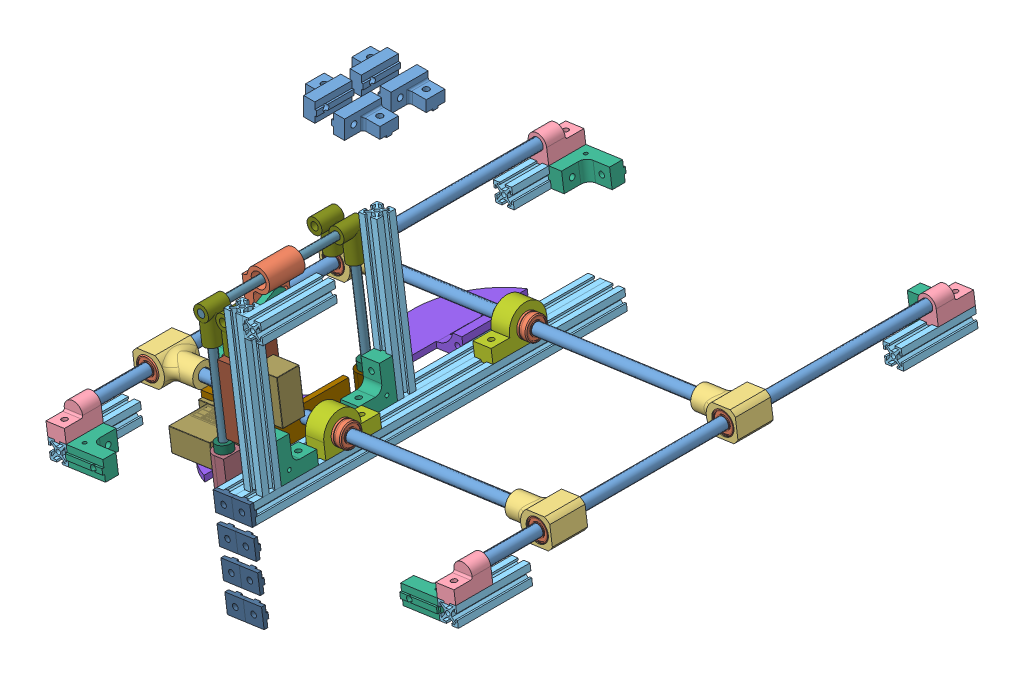
SolidWorks assembly BigRobotFork2019Assembly, configuration Default. Lengths in mm.
Overall size (226.91 110.53 282).
63 component instances, 24 part files, 138 mates.
Components (placement in the parent):
- LinearShaft6mm_differentLengths-1: LinearShaft6mm_differentLengths [250mm] at (75.8296 107.6087 84.7425) size (6 6 250)
- Lineare_bearing_LMUU_serie-1: Lineare_bearing_LMUU_serie [LM6UU] at (75.8296 107.6087 290.7425) x (1 0 0) z (0 -1 0) size (12 19 12)
- LMUU6mm_Support_PerpendicularJunction_Shaft6mm-1: LMUU6mm_Support_PerpendicularJunction_Shaft6mm [Default] at (75.8296 107.6087 290.2425) x (-0.99016 -0.139942 0) z (0 0 1) size (28.5 15.22 19)
- ShaftMakerBeamSupport-1: ShaftMakerBeamSupport [Default] at (75.8296 107.6087 349.7425) x (-0.139942 0.99016 0) z (0 0 -1) size (14 10 20)
- Makerbeam50-1000mm-1: Makerbeam50-1000mm [40mm] at (77.6489 94.7366 349.7425) x (-0.139942 0.99016 0) z (0 0 -1) size (10 10 40)
- Bracket_L_Big_20x20-1: Bracket_L_Big_20x20 [Default] at (81.9 100.3872 349.7425) x (0 0 -1) z (0.139942 -0.99016 0) size (46 46 10)
- Makerbeam50-1000mm-2: Makerbeam50-1000mm [40mm] at (77.6489 94.7366 109.7425) x (-0.139942 0.99016 0) z (0 0 -1) size (10 10 40)
- Bracket_L_Big_20x20-2: Bracket_L_Big_20x20 [Default] at (83.2994 90.4856 69.7425) x (0 0 1) z (-0.139942 0.99016 0) size (46 46 10)
- ShaftMakerBeamSupport-2: ShaftMakerBeamSupport [Default] at (75.8296 107.6087 69.7425) x (-0.139942 0.99016 0) z (0 0 1) size (14 10 20)
- Lineare_bearing_LMUU_serie-2: Lineare_bearing_LMUU_serie [LM6UU] at (75.8296 107.6087 190.2425) x (1 0 0) z (0 -1 0) size (12 19 12)
- LMUU6mm_Support_PerpendicularJunction_Shaft6mm-2: LMUU6mm_Support_PerpendicularJunction_Shaft6mm [Default] at (75.8296 107.6087 190.2425) x (-0.99016 -0.139942 0) z (0 0 1) size (28.5 15.22 19)
- LinearShaft6mm_differentLengths-2: LinearShaft6mm_differentLengths [200mm] at (279.8025 136.4367 190.2425) x (0.121504 -0.859704 -0.49613) z (-0.99016 -0.139942 0) size (6 6 200)
- LinearShaft6mm_differentLengths-3: LinearShaft6mm_differentLengths [200mm] at (279.8025 136.4367 290.2425) x (-0.022059 0.156081 0.987498) z (-0.99016 -0.139942 0) size (6 6 200)
- LMUU6mm_Support_PerpendicularJunction_Shaft6mm-3: LMUU6mm_Support_PerpendicularJunction_Shaft6mm [Default] at (285.7435 137.2764 190.2425) x (0.99016 0.139942 0) z (0 0 1) size (28.5 15.22 19)
- LMUU6mm_Support_PerpendicularJunction_Shaft6mm-4: LMUU6mm_Support_PerpendicularJunction_Shaft6mm [Default] at (285.7435 137.2764 290.2425) x (0.99016 0.139942 0) z (0 0 1) size (28.5 15.22 19)
- LinearShaft6mm_differentLengths-4: LinearShaft6mm_differentLengths [250mm] at (285.7435 137.2764 84.7425) size (6 6 250)
- Lineare_bearing_LMUU_serie-3: Lineare_bearing_LMUU_serie [LM6UU] at (285.7435 137.2764 190.2425) x (1 0 0) z (0 -1 0) size (12 19 12)
- Lineare_bearing_LMUU_serie-4: Lineare_bearing_LMUU_serie [LM6UU] at (285.7435 137.2764 290.2425) x (1 0 0) z (0 -1 0) size (12 19 12)
- ShaftMakerBeamSupport-3: ShaftMakerBeamSupport [Default] at (285.7435 137.2764 349.7425) x (-0.139942 0.99016 0) z (0 0 -1) size (14 10 20)
- Makerbeam50-1000mm-3: Makerbeam50-1000mm [40mm] at (287.5627 124.4043 309.7425) x (-0.139942 0.99016 0) z (0 0 1) size (10 10 40)
- Bracket_L_Big_20x20-3: Bracket_L_Big_20x20 [Default] at (283.3117 118.7538 349.7425) x (0 0 -1) z (-0.139942 0.99016 0) size (46 46 10)
- ShaftMakerBeamSupport-4: ShaftMakerBeamSupport [Default] at (285.7435 137.2764 69.7425) x (-0.139942 0.99016 0) z (0 0 1) size (14 10 20)
- Makerbeam50-1000mm-4: Makerbeam50-1000mm [40mm] at (287.5627 124.4043 69.7425) x (0.99016 0.139942 0) z (0 0 1) size (10 10 40)
- Bracket_L_Big_20x20-4: Bracket_L_Big_20x20 [Default] at (281.9122 128.6554 69.7425) x (0 0 1) z (0.139942 -0.99016 0) size (46 46 10)
- Lineare_bearing_LMUU_serie-5: Lineare_bearing_LMUU_serie [LM6UU] at (166.7867 120.4639 290.2425) x (-0.028348 0.200578 -0.979267) z (0.13704 -0.969631 -0.202572) size (12 19 12)
- Makerbeam50-1000mm-5: Makerbeam50-1000mm [200mm] at (158.2092 106.1224 139.2425) x (0.99016 0.139942 0) z (0 0 1) size (10 10 200)
- Lineare_bearing_LMUU_serie-6: Lineare_bearing_LMUU_serie [LM6UU] at (166.7867 120.4639 190.2425) x (0.127501 -0.902132 -0.412192) z (-0.057683 0.408136 -0.911097) size (12 19 12)
- LM6UU_MakerBeamSupport-2: LM6UU_MakerBeamSupport [Default] at (171.2424 121.0936 190.2425) x (0 0 1) z (-0.99016 -0.139942 0) size (30 19 10)
- ForkBottomBlock-1: ForkBottomBlock [Default] at (147.6079 109.6738 290.2425) x (0 0 -1) z (0.139942 -0.99016 0) size (74.16 41 10)
- ForkBottomBlock-2: ForkBottomBlock [Default] at (147.6079 109.6738 190.2425) x (0 0 -1) z (0.139942 -0.99016 0) size (74.16 41 10)
- ForkRotatingBottomPlateSupport-1: ForkRotatingBottomPlateSupport [Default] at (152.2788 112.3539 290.2425) x (0.139942 -0.99016 0) z (0 0 1) size (24 41 48)
- Makerbeam50-1000mm-6: Makerbeam50-1000mm [200mm] at (168.1108 107.5219 139.2425) x (-0.99016 -0.139942 0) z (0 0 1) size (10 10 200)
- MakerBeamEndSquare3mm-1: MakerBeamEndSquare3mm [Default] at (158.2092 106.1224 339.2425) x (-0.139942 0.99016 0) z (0 0 1) size (55 20 3)
- LM6UU_MakerBeamSupport-3: LM6UU_MakerBeamSupport [Default] at (161.3408 119.6942 290.2425) x (0 0 -1) z (0.99016 0.139942 0) size (30 19 10)
- Makerbeam50-1000mm-7: Makerbeam50-1000mm [80mm] at (156.2158 191.6854 329.2425) x (0.99016 0.139942 0) z (0.139942 -0.99016 0) size (10 10 80)
- Bracket_L_Big_20x20-5: Bracket_L_Big_20x20 [Default] at (162.4603 111.773 324.2425) x (0 0 -1) z (0.99016 0.139942 0) size (46 46 10)
- MG90s_servoSupport1-1: MG90s_servoSupport1 [Default] at (150.2814 147.9243 324.2425) x (0 0 1) z (-0.139942 0.99016 0) size (25 12 35)
- MG90s_servo-1: MG90s_servo [Default] at (150.2464 148.1719 317.7425) x (-0.139942 0.99016 0) z (0.99016 0.139942 0) size (32.5 12 34)
- LM4UU_MakerBeamSupport_DoubleLength-1: LM4UU_MakerBeamSupport_DoubleLength [Default] at (149.0073 99.7722 328.7425) x (0 0 -1) z (-0.139942 0.99016 0) size (20 11.5 20)
- LinearShaft4mm_differentLengths-1: LinearShaft4mm_differentLengths [85mm] at (137.8431 178.7652 328.7425) x (0.989185 0.139804 -0.044354) z (0.139942 -0.99016 0) size (4 4 85)
- Lineare_bearing_LM4UU-1: Lineare_bearing_LM4UU [Default] at (148.1677 105.7132 328.7425) x (0.139942 -0.99016 0) z (-0.471678 -0.066663 0.879247) size (12 8 8)
- Lineare_bearing_LM4UU-2: Lineare_bearing_LM4UU [Default] at (146.4884 117.5951 328.7425) x (-0.139942 0.99016 0) z (0.301825 0.042658 0.952409) size (12 8 8)
- LinearShaft4mm_PerpendicularJuntion-1: LinearShaft4mm_PerpendicularJuntion [Default] at (137.5632 180.7455 332.7425) x (-0.139942 0.99016 0) z (0 0 -1) size (19 20 12)
- MG90s_servo-2: MG90s_servo [Default] at (128.8378 112.0707 308.5425) x (0.99016 0.139942 0) z (0 0 1) size (32.5 12 34)
- MG90s_armSingle-1: MG90s_armSingle [Default] at (134.0361 112.8054 295.5425) x (-0.759643 -0.65034 0) z (0 0 1) size (24 6.8 2)
- LinearShaft4mm_PerpendicularJuntion-2: LinearShaft4mm_PerpendicularJuntion [Default] at (137.5632 180.7455 247.7425) x (-0.139942 0.99016 0) z (0 0 1) size (19 20 12)
- LinearShaft4mm_differentLengths-2: LinearShaft4mm_differentLengths [85mm] at (149.7381 94.6016 251.7425) x (0.912888 0.129021 0.387285) z (-0.139942 0.99016 0) size (4 4 85)
- LM4UU_MakerBeamSupport_DoubleLengthRight-1: LM4UU_MakerBeamSupport_DoubleLengthRight [Default] at (150.4068 89.8706 251.7425) x (0 0 1) z (0.139942 -0.99016 0) size (20 11.5 20)
- Lineare_bearing_LM4UU-3: Lineare_bearing_LM4UU [Default] at (148.1677 105.7132 251.7425) x (0.139942 -0.99016 0) z (0 0 1) size (12 8 8)
- Lineare_bearing_LM4UU-4: Lineare_bearing_LM4UU [Default] at (146.4884 117.5951 251.7425) x (0.139942 -0.99016 0) z (0 0 1) size (12 8 8)
- LinearShaft4mm_differentLengths-3: LinearShaft4mm_differentLengths [85mm] at (137.5632 180.7455 247.7425) size (4 4 85)
- Makerbeam50-1000mm-8: Makerbeam50-1000mm [40mm] at (166.8171 188.1341 294.2425) x (-0.99016 -0.139942 0) z (0 0 1) size (10 10 40)
- Bracket_L20x15_CrossBig-1: Bracket_L20x15_CrossBig [Default] at (98.3213 189.6121 177.1609) size (40 11 45)
- Bracket_L_Big_20x20-6: Bracket_L_Big_20x20 [Default] at (162.4603 111.773 251.7425) x (0 0 1) z (-0.99016 -0.139942 0) size (46 46 10)
- Makerbeam50-1000mm-9: Makerbeam50-1000mm [80mm] at (146.3142 190.286 246.7425) x (0.99016 0.139942 0) z (0.139942 -0.99016 0) size (10 10 80)
- LM4UUSupport_WithRollingBallSupport-1: LM4UUSupport_WithRollingBallSupport [Default] at (137.5632 180.7455 292.2268) x (0.139942 -0.99016 0) z (0 0 1) size (26 15 19)
- Lineare_bearing_LM4UU-5: Lineare_bearing_LM4UU [Default] at (137.5632 180.7455 288.7268) x (0 0 -1) z (0.745964 -0.665986 0) size (12 8 8)
- -MR623ZZ-assem-1: -MR623ZZ-assem [Default] at (133.4415 167.0338 292.2268) x (0.99016 0.139942 0) z (0 0 1) size (4 10 10)
  - mr623zz-cen-1: mr623zz-cen [Default] at (0.5 0 0) size (0.23 8.2 8.2)
  - mr623zz-ext-1: mr623zz-ext [Default] at origin size (4 10 10)
  - mr623zz-int-1: mr623zz-int [Default] at origin size (4 5.2 5.2)
  - mr623zz-cen-2: mr623zz-cen [Default] at (-0.5 0 0) x (-1 0 0) z (0 0 1) size (0.23 8.2 8.2)
- MG90SFlatRudderExtension30mm-1: MG90SFlatRudderExtension30mm [Default] at (138.6199 151.8309 317.7425) x (-0.0736 0.520758 -0.850525) z (0.99016 0.139942 0) size (43 16 4.5)
Mates (geometry in assembly coordinates):
- Concentric1: concentric anti-aligned: cylinder of LinearShaft6mm_differentLengths-1 through (75.8296 107.6087 334.7425) axis (0 0 -1) radius 3; cylinder of Lineare_bearing_LMUU_serie-1 through (75.8296 107.6087 300.2425) axis (0 0 1) radius 3
- Concentric2: concentric anti-aligned: cylinder of Lineare_bearing_LMUU_serie-1 through (75.8296 107.6087 300.2425) axis (0 0 1) radius 6; cylinder of LMUU6mm_Support_PerpendicularJunction_Shaft6mm-1 through (75.8296 107.6087 299.7425) axis (0 0 -1) radius 6
- Coincident1: coincident aligned: plane of Lineare_bearing_LMUU_serie-1 through (75.8296 107.6087 299.7425) normal (0 0 1); circle of LMUU6mm_Support_PerpendicularJunction_Shaft6mm-1
- Concentric3: concentric aligned: cylinder of LinearShaft6mm_differentLengths-1 through (75.8296 107.6087 334.7425) axis (0 0 -1) radius 3; cylinder of ShaftMakerBeamSupport-1 through (75.8296 107.6087 334.7425) axis (0 0 -1) radius 3.1
- Coincident2: coincident anti-aligned: plane of ShaftMakerBeamSupport-1 through (81.9 100.3872 329.7425) normal (0.139942 -0.99016 0); plane of Makerbeam50-1000mm-1 through (81.9 100.3872 309.7425) normal (-0.139942 0.99016 0)
- Coincident3: coincident aligned: plane of ShaftMakerBeamSupport-1 through (81.9 100.3872 329.7425) normal (0.99016 0.139942 0); plane of Makerbeam50-1000mm-1 through (82.3898 96.9216 309.7425) normal (0.99016 0.139942 0)
- Coincident4: coincident anti-aligned: plane of LinearShaft6mm_differentLengths-1 through (75.8296 107.6087 334.7425) normal (0 0 1); plane of ShaftMakerBeamSupport-1 through (75.8296 107.6087 334.7425) normal (0 0 -1)
- Coincident5: coincident anti-aligned: plane of Makerbeam50-1000mm-1 through (82.3898 96.9216 309.7425) normal (0.99016 0.139942 0); plane of Bracket_L_Big_20x20-1 through (83.2994 90.4856 349.7425) normal (-0.99016 -0.139942 0)
- Coincident6: coincident aligned: plane of Makerbeam50-1000mm-1 through (79.8338 89.9958 309.7425) normal (0.139942 -0.99016 0); plane of Bracket_L_Big_20x20-1 through (94.1911 92.0249 338.7425) normal (0.139942 -0.99016 0)
- Coincident7: coincident aligned: plane of Makerbeam50-1000mm-1 through (77.6489 94.7366 349.7425) normal (0 0 1); plane of Bracket_L_Big_20x20-1 through (103.1026 93.2844 349.7425) normal (0 0 1)
- Concentric4: concentric anti-aligned: cylinder of LinearShaft6mm_differentLengths-1 through (75.8296 107.6087 334.7425) axis (0 0 -1) radius 3; cylinder of ShaftMakerBeamSupport-2 through (75.8296 107.6087 84.7425) axis (0 0 1) radius 3.1
- Coincident8: coincident anti-aligned: plane of LinearShaft6mm_differentLengths-1 through (75.8296 107.6087 84.7425) normal (0 0 -1); plane of ShaftMakerBeamSupport-2 through (75.8296 107.6087 84.7425) normal (0 0 1)
- Coincident9: coincident aligned: plane of ShaftMakerBeamSupport-1 through (81.9 100.3872 329.7425) normal (0.139942 -0.99016 0); plane of ShaftMakerBeamSupport-2 through (71.9984 98.9877 89.7425) normal (0.139942 -0.99016 0)
- Coincident10: coincident aligned: plane of ShaftMakerBeamSupport-1 through (75.8296 107.6087 349.7425) normal (0 0 1); plane of Makerbeam50-1000mm-1 through (77.6489 94.7366 349.7425) normal (0 0 1)
- Parallel1: parallel aligned: plane of LMUU6mm_Support_PerpendicularJunction_Shaft6mm-1 through (81.8052 100.8787 280.7425) normal (0.139942 -0.99016 0); plane of Makerbeam50-1000mm-2 through (79.8338 89.9958 69.7425) normal (0.139942 -0.99016 0)
- Concentric5: concentric anti-aligned: cylinder of LinearShaft6mm_differentLengths-1 through (75.8296 107.6087 334.7425) axis (0 0 -1) radius 3; cylinder of Lineare_bearing_LMUU_serie-2 through (75.8296 107.6087 199.7425) axis (0 0 1) radius 3
- Concentric6: concentric anti-aligned: cylinder of Lineare_bearing_LMUU_serie-2 through (75.8296 107.6087 199.7425) axis (0 0 1) radius 6; cylinder of LMUU6mm_Support_PerpendicularJunction_Shaft6mm-2 through (75.8296 107.6087 199.7425) axis (0 0 -1) radius 6
- Coincident12: coincident aligned: plane of Lineare_bearing_LMUU_serie-2 through (78.8296 107.6087 199.7425) normal (0 0 1); plane of LMUU6mm_Support_PerpendicularJunction_Shaft6mm-2 through (75.8296 107.6087 199.7425) normal (0 0 1)
- Coincident13: coincident aligned: plane of LMUU6mm_Support_PerpendicularJunction_Shaft6mm-1 through (79.7061 115.7311 280.7425) normal (-0.139942 0.99016 0); plane of LMUU6mm_Support_PerpendicularJunction_Shaft6mm-2 through (79.7061 115.7311 180.7425) normal (-0.139942 0.99016 0)
- Concentric7: concentric anti-aligned: cylinder of LMUU6mm_Support_PerpendicularJunction_Shaft6mm-2 through (96.623 110.5475 190.2425) axis (-0.99016 -0.139942 0) radius 3; cylinder of LinearShaft6mm_differentLengths-2 through (81.7706 108.4484 190.2425) axis (0.99016 0.139942 0) radius 3
- Tangent1: tangent anti-aligned: cylinder of Lineare_bearing_LMUU_serie-2 through (75.8296 107.6087 199.7425) axis (0 0 1) radius 6; plane of LinearShaft6mm_differentLengths-2 through (81.7706 108.4484 190.2425) normal (-0.99016 -0.139942 0)
- Concentric8: concentric anti-aligned: cylinder of LMUU6mm_Support_PerpendicularJunction_Shaft6mm-1 through (96.623 110.5475 290.2425) axis (-0.99016 -0.139942 0) radius 3; cylinder of LinearShaft6mm_differentLengths-3 through (81.7706 108.4484 290.2425) axis (0.99016 0.139942 0) radius 3
- Tangent2: tangent anti-aligned: cylinder of Lineare_bearing_LMUU_serie-1 through (75.8296 107.6087 300.2425) axis (0 0 1) radius 6; plane of LinearShaft6mm_differentLengths-3 through (81.7706 108.4484 290.2425) normal (-0.99016 -0.139942 0)
- Concentric9: concentric aligned: cylinder of LinearShaft6mm_differentLengths-2 through (81.7706 108.4484 190.2425) axis (0.99016 0.139942 0) radius 3; cylinder of LMUU6mm_Support_PerpendicularJunction_Shaft6mm-3 through (264.9502 134.3376 190.2425) axis (0.99016 0.139942 0) radius 3
- Tangent3: tangent anti-aligned: plane of LinearShaft6mm_differentLengths-2 through (279.8025 136.4367 190.2425) normal (0.99016 0.139942 0); cylinder of LMUU6mm_Support_PerpendicularJunction_Shaft6mm-3 through (285.7435 137.2764 199.7425) axis (0 0 -1) radius 6
- Coincident14: coincident aligned: plane of LMUU6mm_Support_PerpendicularJunction_Shaft6mm-2 through (81.8052 100.8787 180.7425) normal (0.139942 -0.99016 0); plane of LMUU6mm_Support_PerpendicularJunction_Shaft6mm-3 through (281.8671 129.154 180.7425) normal (0.139942 -0.99016 0)
- Concentric10: concentric aligned: cylinder of LinearShaft6mm_differentLengths-3 through (81.7706 108.4484 290.2425) axis (0.99016 0.139942 0) radius 3; cylinder of LMUU6mm_Support_PerpendicularJunction_Shaft6mm-4 through (264.9502 134.3376 290.2425) axis (0.99016 0.139942 0) radius 3
- Tangent4: tangent anti-aligned: plane of LinearShaft6mm_differentLengths-3 through (279.8025 136.4367 290.2425) normal (0.99016 0.139942 0); cylinder of LMUU6mm_Support_PerpendicularJunction_Shaft6mm-4 through (285.7435 137.2764 299.7425) axis (0 0 -1) radius 6
- Concentric11: concentric anti-aligned: cylinder of LMUU6mm_Support_PerpendicularJunction_Shaft6mm-3 through (285.7435 137.2764 199.7425) axis (0 0 -1) radius 6; cylinder of Lineare_bearing_LMUU_serie-3 through (285.7435 137.2764 199.7425) axis (0 0 1) radius 6
- Coincident15: coincident aligned: plane of LMUU6mm_Support_PerpendicularJunction_Shaft6mm-3 through (285.7435 137.2764 180.7425) normal (0 0 -1); plane of Lineare_bearing_LMUU_serie-3 through (291.2435 137.2764 180.7425) normal (0 0 -1)
- Concentric12: concentric anti-aligned: cylinder of LMUU6mm_Support_PerpendicularJunction_Shaft6mm-4 through (285.7435 137.2764 299.7425) axis (0 0 -1) radius 6; cylinder of Lineare_bearing_LMUU_serie-4 through (285.7435 137.2764 299.7425) axis (0 0 1) radius 6
- Coincident16: coincident aligned: plane of LMUU6mm_Support_PerpendicularJunction_Shaft6mm-4 through (285.7435 137.2764 280.7425) normal (0 0 -1); plane of Lineare_bearing_LMUU_serie-4 through (291.2435 137.2764 280.7425) normal (0 0 -1)
- Concentric13: concentric anti-aligned: cylinder of LinearShaft6mm_differentLengths-4 through (285.7435 137.2764 334.7425) axis (0 0 -1) radius 3; cylinder of Lineare_bearing_LMUU_serie-3 through (285.7435 137.2764 199.7425) axis (0 0 1) radius 3
- Concentric14: concentric aligned: cylinder of LinearShaft6mm_differentLengths-4 through (285.7435 137.2764 334.7425) axis (0 0 -1) radius 3; cylinder of ShaftMakerBeamSupport-3 through (285.7435 137.2764 334.7425) axis (0 0 -1) radius 3.1
- Coincident17: coincident anti-aligned: plane of LinearShaft6mm_differentLengths-4 through (285.7435 137.2764 334.7425) normal (0 0 1); plane of ShaftMakerBeamSupport-3 through (285.7435 137.2764 334.7425) normal (0 0 -1)
- Coincident18: coincident anti-aligned: plane of ShaftMakerBeamSupport-3 through (291.8138 130.0548 329.7425) normal (0.139942 -0.99016 0); plane of Makerbeam50-1000mm-3 through (281.9122 128.6554 349.7425) normal (-0.139942 0.99016 0)
- Coincident19: coincident aligned: plane of ShaftMakerBeamSupport-3 through (291.8138 130.0548 329.7425) normal (0.99016 0.139942 0); plane of Makerbeam50-1000mm-3 through (292.3036 126.5892 349.7425) normal (0.99016 0.139942 0)
- Parallel3: parallel aligned: plane of Makerbeam50-1000mm-1 through (73.3978 89.0861 309.7425) normal (0.139942 -0.99016 0); plane of Makerbeam50-1000mm-3 through (293.2133 120.1532 349.7425) normal (0.139942 -0.99016 0)
- Coincident22: coincident aligned: plane of Makerbeam50-1000mm-1 through (77.6489 94.7366 349.7425) normal (0 0 1); plane of Makerbeam50-1000mm-3 through (287.5627 124.4043 349.7425) normal (0 0 1)
- Coincident23: coincident aligned: plane of ShaftMakerBeamSupport-3 through (285.7435 137.2764 349.7425) normal (0 0 1); plane of Makerbeam50-1000mm-3 through (287.5627 124.4043 349.7425) normal (0 0 1)
- Coincident24: coincident anti-aligned: plane of Makerbeam50-1000mm-3 through (283.3117 118.7538 349.7425) normal (-0.99016 -0.139942 0); plane of Bracket_L_Big_20x20-3 through (281.9122 128.6554 349.7425) normal (0.99016 0.139942 0)
- Coincident25: coincident aligned: plane of Makerbeam50-1000mm-3 through (287.5627 124.4043 349.7425) normal (0 0 1); plane of Bracket_L_Big_20x20-3 through (262.109 125.8566 349.7425) normal (0 0 1)
- Coincident26: coincident aligned: plane of Makerbeam50-1000mm-3 through (286.7772 119.2436 349.7425) normal (0.139942 -0.99016 0); plane of Bracket_L_Big_20x20-3 through (272.4199 117.2144 338.7425) normal (0.139942 -0.99016 0)
- Concentric15: concentric anti-aligned: cylinder of LinearShaft6mm_differentLengths-4 through (285.7435 137.2764 334.7425) axis (0 0 -1) radius 3; cylinder of ShaftMakerBeamSupport-4 through (285.7435 137.2764 84.7425) axis (0 0 1) radius 3.1
- Coincident27: coincident anti-aligned: plane of LinearShaft6mm_differentLengths-4 through (285.7435 137.2764 84.7425) normal (0 0 -1); plane of ShaftMakerBeamSupport-4 through (285.7435 137.2764 84.7425) normal (0 0 1)
- Coincident28: coincident aligned: plane of ShaftMakerBeamSupport-3 through (285.8834 136.2862 349.7425) normal (-0.139942 0.99016 0); plane of ShaftMakerBeamSupport-4 through (285.8834 136.2862 69.7425) normal (-0.139942 0.99016 0)
- Coincident29: coincident anti-aligned: plane of ShaftMakerBeamSupport-4 through (288.2988 129.558 89.7425) normal (0.139942 -0.99016 0); plane of Makerbeam50-1000mm-4 through (288.3483 129.565 109.7425) normal (-0.139942 0.99016 0)
- Coincident30: coincident aligned: plane of ShaftMakerBeamSupport-4 through (291.8138 130.0548 89.7425) normal (0.99016 0.139942 0); plane of Makerbeam50-1000mm-4 through (291.8138 130.0548 109.7425) normal (0.99016 0.139942 0)
- Coincident31: coincident aligned: plane of Makerbeam50-1000mm-2 through (77.6489 94.7366 69.7425) normal (0 0 -1); plane of Makerbeam50-1000mm-4 through (287.5627 124.4043 69.7425) normal (0 0 -1)
- Coincident32: coincident aligned: plane of Makerbeam50-1000mm-4 through (286.7772 119.2436 109.7425) normal (0.139942 -0.99016 0); plane of Bracket_L_Big_20x20-4 through (272.4199 117.2144 80.7425) normal (0.139942 -0.99016 0)
- Coincident33: coincident anti-aligned: plane of Makerbeam50-1000mm-4 through (283.3117 118.7538 109.7425) normal (-0.99016 -0.139942 0); plane of Bracket_L_Big_20x20-4 through (283.3117 118.7538 69.7425) normal (0.99016 0.139942 0)
- Coincident34: coincident aligned: plane of Makerbeam50-1000mm-4 through (287.5627 124.4043 69.7425) normal (0 0 -1); plane of Bracket_L_Big_20x20-4 through (263.5085 115.955 69.7425) normal (0 0 -1)
- Distance1: distance = 4.5 mm aligned: plane of Lineare_bearing_LMUU_serie-5; plane of ? through (245.1356 52.8542 137.3823) normal (0.936759 -0.349976 0)
- Concentric17: concentric aligned: cylinder of LinearShaft6mm_differentLengths-3 through (81.7706 108.4484 290.2425) axis (0.99016 0.139942 0) radius 3; cylinder of Lineare_bearing_LMUU_serie-5 through (176.1932 121.7934 290.2425) axis (0.99016 0.139942 0) radius 3
- Coincident36: coincident anti-aligned: plane of ? through (242.3358 45.3602 147.3823) normal (-0.349976 -0.936759 0); plane of Makerbeam50-1000mm-5
- Concentric18: concentric anti-aligned: cylinder of LinearShaft6mm_differentLengths-2 through (81.7706 108.4484 190.2425) axis (0.99016 0.139942 0) radius 3; cylinder of Lineare_bearing_LMUU_serie-6 through (157.3801 119.1345 190.2425) axis (-0.99016 -0.139942 0) radius 3
- Coincident38: coincident anti-aligned: plane of Makerbeam50-1000mm-5 through (158.9948 111.2832 339.2425) normal (-0.139942 0.99016 0); plane of LM6UU_MakerBeamSupport-2 through (162.4603 111.773 180.2425) normal (0.139942 -0.99016 0)
- Coincident40: coincident aligned: plane of Lineare_bearing_LMUU_serie-5 through (175.6981 121.7234 290.2425) normal (0.99016 0.139942 0); plane of Lineare_bearing_LMUU_serie-6 through (175.6981 121.7234 190.2425) normal (0.99016 0.139942 0)
- Concentric20: concentric aligned: cylinder of ForkBottomBlock-1 through (145.3371 104.3032 253.1615) axis (0 0 1) radius 1.5; cylinder of ForkRotatingBottomPlateSupport-1 through (145.3371 104.3032 266.2425) axis (0 0 1) radius 1.25
- Coincident41: coincident anti-aligned: plane of ForkBottomBlock-1 through (134.1549 97.6731 302.2425) normal (0 0 1); plane of ForkRotatingBottomPlateSupport-1 through (114.3517 94.8743 302.2425) normal (0 0 -1)
- Coincident42: coincident anti-aligned: plane of Makerbeam50-1000mm-5 through (153.9581 100.4719 339.2425) normal (-0.99016 -0.139942 0); plane of ForkRotatingBottomPlateSupport-1 through (153.4613 103.987 314.2425) normal (0.99016 0.139942 0)
- Coincident44: coincident aligned: plane of Makerbeam50-1000mm-5 through (158.2092 106.1224 339.2425) normal (0 0 1); plane of Makerbeam50-1000mm-6 through (168.1108 107.5219 339.2425) normal (0 0 1)
- Coincident45: coincident anti-aligned: plane of Makerbeam50-1000mm-5 through (163.3699 105.3369 339.2425) normal (0.99016 0.139942 0); plane of Makerbeam50-1000mm-6 through (163.8597 101.8714 339.2425) normal (-0.99016 -0.139942 0)
- Coincident46: coincident aligned: plane of Makerbeam50-1000mm-5 through (157.4237 100.9617 339.2425) normal (0.139942 -0.99016 0); plane of Makerbeam50-1000mm-6 through (167.3253 102.3611 339.2425) normal (0.139942 -0.99016 0)
- Concentric21: concentric aligned: cylinder of Makerbeam50-1000mm-6 through (168.1108 107.5219 339.2425) axis (0 0 -1) radius 1.25; cylinder of MakerBeamEndSquare3mm-1 through (168.1108 107.5219 341.2425) axis (0 0 -1) radius 1.5
- Coincident47: coincident anti-aligned: plane of Makerbeam50-1000mm-6 through (168.1108 107.5219 339.2425) normal (0 0 1); plane of MakerBeamEndSquare3mm-1 through (168.1108 107.5219 339.2425) normal (0 0 -1)
- Concentric22: concentric aligned: cylinder of Makerbeam50-1000mm-5 through (158.2092 106.1224 339.2425) axis (0 0 -1) radius 1.25; cylinder of MakerBeamEndSquare3mm-1 through (158.2092 106.1224 341.2425) axis (0 0 -1) radius 1.5
- Coincident48: coincident aligned: plane of LM6UU_MakerBeamSupport-2 through (171.2424 121.0936 190.2425) normal (0.99016 0.139942 0); plane of Makerbeam50-1000mm-6 through (172.3619 113.1724 339.2425) normal (0.99016 0.139942 0)
- Distance3: distance = 5 mm aligned: plane of Lineare_bearing_LMUU_serie-6 through (176.8944 116.8316 187.9755) normal (0.99016 0.139942 0); plane of LM6UU_MakerBeamSupport-2 through (171.2424 121.0936 190.2425) normal (0.99016 0.139942 0)
- Concentric25: concentric anti-aligned: cylinder of Lineare_bearing_LMUU_serie-6 through (157.3801 119.1345 190.2425) axis (-0.99016 -0.139942 0) radius 6; cylinder of LM6UU_MakerBeamSupport-2 through (161.3408 119.6942 190.2425) axis (0.99016 0.139942 0) radius 6
- Concentric27: concentric anti-aligned: cylinder of Lineare_bearing_LMUU_serie-5 through (176.1932 121.7934 290.2425) axis (0.99016 0.139942 0) radius 6; cylinder of LM6UU_MakerBeamSupport-3 through (171.2424 121.0936 290.2425) axis (-0.99016 -0.139942 0) radius 6
- Coincident50: coincident aligned: plane of LM6UU_MakerBeamSupport-2 through (171.2424 121.0936 190.2425) normal (0.99016 0.139942 0); plane of LM6UU_MakerBeamSupport-3 through (171.2424 121.0936 290.2425) normal (0.99016 0.139942 0)
- Coincident51: coincident aligned: plane of LM6UU_MakerBeamSupport-2 through (161.4807 118.7041 210.2425) normal (-0.139942 0.99016 0); plane of LM6UU_MakerBeamSupport-3 through (171.3823 120.1035 270.2425) normal (-0.139942 0.99016 0)
- Distance4: distance = 60 mm anti-aligned: plane of LM6UU_MakerBeamSupport-2 through (162.4603 111.773 210.2425) normal (0 0 1); plane of LM6UU_MakerBeamSupport-3 through (172.3619 113.1724 270.2425) normal (0 0 -1)
- Coincident53: coincident anti-aligned: plane of Makerbeam50-1000mm-6 through (168.8964 112.6826 339.2425) normal (-0.139942 0.99016 0); plane of Makerbeam50-1000mm-7 through (167.4111 112.4727 329.2425) normal (0.139942 -0.99016 0)
- Coincident54: coincident aligned: plane of Makerbeam50-1000mm-6 through (172.3619 113.1724 339.2425) normal (0.99016 0.139942 0); plane of Makerbeam50-1000mm-7 through (172.3619 113.1724 327.7425) normal (0.99016 0.139942 0)
- Distance5: distance = 5 mm: line of MakerBeamEndSquare3mm-1 through (165.9754 112.2697 339.2425) axis (-0.99016 -0.139942 0); plane of Makerbeam50-1000mm-7 through (162.4603 111.773 334.2425) normal (0 0 1)
- Coincident56: coincident aligned: plane of Makerbeam50-1000mm-6 through (172.3619 113.1724 339.2425) normal (0.99016 0.139942 0); plane of Bracket_L_Big_20x20-5 through (170.8226 124.0641 313.2425) normal (0.99016 0.139942 0)
- Coincident57: coincident anti-aligned: plane of Makerbeam50-1000mm-7 through (168.8964 112.6826 324.2425) normal (0 0 -1); plane of Bracket_L_Big_20x20-5 through (169.5631 132.9756 324.2425) normal (0 0 1)
- Coincident58: coincident anti-aligned: plane of Makerbeam50-1000mm-6 through (168.8964 112.6826 339.2425) normal (-0.139942 0.99016 0); plane of Bracket_L_Big_20x20-5 through (172.3619 113.1724 324.2425) normal (0.139942 -0.99016 0)
- Distance6: distance = 4 mm anti-aligned: plane of LM6UU_MakerBeamSupport-3 through (171.2424 121.0936 300.2425) normal (0 0 1); plane of Bracket_L_Big_20x20-5 through (172.3619 113.1724 304.2425) normal (0 0 -1)
- Coincident61: coincident aligned: plane of Makerbeam50-1000mm-7 through (168.8964 112.6826 334.2425) normal (0 0 1); plane of MG90s_servoSupport1-1 through (147.8324 165.2521 334.2425) normal (0 0 1)
- Distance7: distance = 30 mm aligned: plane of MG90s_servoSupport1-1 through (152.7304 130.5966 324.2425) normal (0.139942 -0.99016 0); plane of Makerbeam50-1000mm-6 through (173.7613 103.2708 339.2425) normal (0.139942 -0.99016 0)
- Coincident63: coincident anti-aligned: plane of MG90s_servoSupport1-1 through (147.8324 165.2521 309.2425) normal (-0.99016 -0.139942 0); plane of MG90s_servo-1 through (150.2464 148.1719 317.7425) normal (0.99016 0.139942 0)
- Coincident64: coincident anti-aligned: plane of MG90s_servoSupport1-1 through (146.9399 135.8378 311.7425) normal (0 0 1); plane of MG90s_servo-1 through (147.969 147.85 311.7425) normal (0 0 -1)
- Coincident65: coincident anti-aligned: plane of MG90s_servoSupport1-1 through (143.7213 158.6115 311.7425) normal (0.139942 -0.99016 0); plane of MG90s_servo-1 through (169.4654 162.25 311.7425) normal (-0.139942 0.99016 0)
- Coincident66: coincident aligned: plane of Makerbeam50-1000mm-5 through (157.4237 100.9617 339.2425) normal (0.139942 -0.99016 0); plane of LM4UU_MakerBeamSupport_DoubleLength-1 through (149.0073 99.7722 328.7425) normal (0.139942 -0.99016 0)
- Coincident67: coincident anti-aligned: plane of Makerbeam50-1000mm-5 through (153.9581 100.4719 339.2425) normal (-0.99016 -0.139942 0); plane of LM4UU_MakerBeamSupport_DoubleLength-1 through (152.5587 110.3735 334.2425) normal (0.99016 0.139942 0)
- Coincident68: coincident anti-aligned: plane of ForkRotatingBottomPlateSupport-1 through (152.2788 112.3539 314.2425) normal (0 0 1); plane of LM4UU_MakerBeamSupport_DoubleLength-1 through (152.5587 110.3735 314.2425) normal (0 0 -1)
- Distance8: distance = 5 mm: plane of LM4UU_MakerBeamSupport_DoubleLength-1 through (147.6079 109.6738 334.2425) normal (0 0 1); line of MakerBeamEndSquare3mm-1 through (153.4613 103.987 339.2425) axis (0.139942 -0.99016 0)
- Concentric28: concentric anti-aligned: cylinder of LM4UU_MakerBeamSupport_DoubleLength-1 through (147.6079 109.6738 328.7425) axis (0.139942 -0.99016 0) radius 4; cylinder of LinearShaft4mm_differentLengths-1 through (149.7381 94.6016 328.7425) axis (-0.139942 0.99016 0) radius 2
- Concentric29: concentric anti-aligned: cylinder of LM4UU_MakerBeamSupport_DoubleLength-1 through (147.6079 109.6738 328.7425) axis (0.139942 -0.99016 0) radius 4; cylinder of Lineare_bearing_LM4UU-1 through (149.0073 99.7722 328.7425) axis (-0.139942 0.99016 0) radius 4
- Coincident70: coincident aligned: plane of LM4UU_MakerBeamSupport_DoubleLength-1 through (149.0073 99.7722 328.7425) normal (0.139942 -0.99016 0); plane of Lineare_bearing_LM4UU-1 through (152.4897 100.2644 330.648) normal (0.139942 -0.99016 0)
- Concentric30: concentric anti-aligned: cylinder of LinearShaft4mm_differentLengths-1 through (149.7381 94.6016 328.7425) axis (-0.139942 0.99016 0) radius 2; cylinder of Lineare_bearing_LM4UU-2 through (145.6487 123.5361 328.7425) axis (0.139942 -0.99016 0) radius 2
- Coincident71: coincident anti-aligned: plane of Lineare_bearing_LM4UU-1 through (149.0692 111.9002 329.6953) normal (-0.139942 0.99016 0); plane of Lineare_bearing_LM4UU-2 through (145.442 111.3876 329.3522) normal (0.139942 -0.99016 0)
- Concentric32: concentric aligned: cylinder of LinearShaft4mm_differentLengths-1 through (149.7381 94.6016 328.7425) axis (-0.139942 0.99016 0) radius 2; cylinder of LinearShaft4mm_PerpendicularJuntion-1 through (139.6623 165.8931 328.7425) axis (-0.139942 0.99016 0) radius 2
- Tangent6: tangent anti-aligned: plane of LinearShaft4mm_differentLengths-1 through (137.8431 178.7652 328.7425) normal (-0.139942 0.99016 0); cylinder of LinearShaft4mm_PerpendicularJuntion-1 through (137.5632 180.7455 320.7425) axis (0 0 1) radius 2
- Concentric33: concentric anti-aligned: cylinder of MG90s_servo-2 through (134.0361 112.8054 295.5425) axis (0 0 1) radius 2.275; cylinder of MG90s_armSingle-1 through (134.0361 112.8054 297.5425) axis (0 0 -1) radius 1.25
- Coincident73: coincident aligned: plane of MG90s_servo-2 through (134.0361 112.8054 295.5425) normal (0 0 -1); plane of MG90s_armSingle-1 through (134.0361 112.8054 295.5425) normal (0 0 -1)
- Tangent7: tangent anti-aligned: plane of ForkBottomBlock-1 through (143.6367 102.043 327.3235) normal (-0.139942 0.99016 0); cylinder of MG90s_armSingle-1 through (119.9068 100.7091 297.5425) axis (0 0 -1) radius 2
- Coincident82: coincident aligned: plane of Makerbeam50-1000mm-5 through (157.4237 100.9617 339.2425) normal (0.139942 -0.99016 0); plane of ForkBottomBlock-1 through (149.0073 99.7722 290.2425) normal (0.139942 -0.99016 0)
- Concentric34: concentric anti-aligned: cylinder of LinearShaft4mm_PerpendicularJuntion-1 through (137.5632 180.7455 320.7425) axis (0 0 1) radius 2; cylinder of LinearShaft4mm_PerpendicularJuntion-2 through (137.5632 180.7455 259.7425) axis (0 0 -1) radius 2
- Coincident84: coincident anti-aligned: plane of Makerbeam50-1000mm-5 through (153.9581 100.4719 339.2425) normal (-0.99016 -0.139942 0); plane of LM4UU_MakerBeamSupport_DoubleLengthRight-1 through (152.5587 110.3735 246.2425) normal (0.99016 0.139942 0)
- Coincident85: coincident aligned: plane of Makerbeam50-1000mm-5 through (157.4237 100.9617 339.2425) normal (0.139942 -0.99016 0); plane of LM4UU_MakerBeamSupport_DoubleLengthRight-1 through (149.0073 99.7722 251.7425) normal (0.139942 -0.99016 0)
- Coincident86: coincident anti-aligned: plane of ForkRotatingBottomPlateSupport-1 through (152.2788 112.3539 266.2425) normal (0 0 -1); plane of LM4UU_MakerBeamSupport_DoubleLengthRight-1 through (152.5587 110.3735 266.2425) normal (0 0 1)
- Concentric35: concentric anti-aligned: cylinder of LM4UU_MakerBeamSupport_DoubleLengthRight-1 through (147.6079 109.6738 251.7425) axis (0.139942 -0.99016 0) radius 4; cylinder of Lineare_bearing_LM4UU-3 through (149.0073 99.7722 251.7425) axis (-0.139942 0.99016 0) radius 4
- Coincident87: coincident aligned: plane of LM4UU_MakerBeamSupport_DoubleLengthRight-1 through (149.0073 99.7722 251.7425) normal (0.139942 -0.99016 0); plane of Lineare_bearing_LM4UU-3 through (152.968 100.332 251.7425) normal (0.139942 -0.99016 0)
- Coincident88: coincident anti-aligned: plane of Lineare_bearing_LM4UU-3 through (149.3084 111.934 251.7425) normal (-0.139942 0.99016 0); plane of Lineare_bearing_LM4UU-4 through (151.2887 112.2139 251.7425) normal (0.139942 -0.99016 0)
- Concentric36: concentric anti-aligned: cylinder of LM4UU_MakerBeamSupport_DoubleLengthRight-1 through (147.6079 109.6738 251.7425) axis (0.139942 -0.99016 0) radius 4; cylinder of Lineare_bearing_LM4UU-4 through (147.328 111.6541 251.7425) axis (-0.139942 0.99016 0) radius 4
- Concentric37: concentric anti-aligned: cylinder of LinearShaft4mm_differentLengths-2 through (137.8431 178.7652 251.7425) axis (0.139942 -0.99016 0) radius 2; cylinder of Lineare_bearing_LM4UU-4 through (147.328 111.6541 251.7425) axis (-0.139942 0.99016 0) radius 2
- Coincident89: coincident aligned: plane of LinearShaft4mm_differentLengths-1 through (149.7381 94.6016 328.7425) normal (0.139942 -0.99016 0); plane of LinearShaft4mm_differentLengths-2 through (149.7381 94.6016 251.7425) normal (0.139942 -0.99016 0)
- Concentric38: concentric anti-aligned: cylinder of LinearShaft4mm_PerpendicularJuntion-2 through (139.6623 165.8931 251.7425) axis (-0.139942 0.99016 0) radius 2; cylinder of LinearShaft4mm_differentLengths-2 through (137.8431 178.7652 251.7425) axis (0.139942 -0.99016 0) radius 2
- Concentric39: concentric anti-aligned: cylinder of LinearShaft4mm_PerpendicularJuntion-1 through (137.5632 180.7455 320.7425) axis (0 0 1) radius 2; cylinder of LinearShaft4mm_differentLengths-3 through (137.5632 180.7455 332.7425) axis (0 0 -1) radius 2
- Coincident90: coincident aligned: plane of LinearShaft4mm_PerpendicularJuntion-2 through (137.5632 180.7455 247.7425) normal (0 0 -1); plane of LinearShaft4mm_differentLengths-3 through (137.5632 180.7455 247.7425) normal (0 0 -1)
- Coincident91: coincident aligned: plane of Makerbeam50-1000mm-7 through (168.8964 112.6826 334.2425) normal (0 0 1); plane of Makerbeam50-1000mm-8 through (166.8171 188.1341 334.2425) normal (0 0 1)
- Coincident92: coincident anti-aligned: plane of Makerbeam50-1000mm-7 through (172.3619 113.1724 334.2425) normal (0.99016 0.139942 0); plane of Makerbeam50-1000mm-8 through (161.6564 188.9196 334.2425) normal (-0.99016 -0.139942 0)
- Coincident93: coincident aligned: plane of Makerbeam50-1000mm-7 through (156.2158 191.6854 329.2425) normal (-0.139942 0.99016 0); plane of Makerbeam50-1000mm-8 through (167.6026 193.2948 334.2425) normal (-0.139942 0.99016 0)
- Coincident94: coincident anti-aligned: plane of Makerbeam50-1000mm-5 through (158.9948 111.2832 339.2425) normal (-0.139942 0.99016 0); plane of Bracket_L_Big_20x20-6 through (152.5587 110.3735 251.7425) normal (0.139942 -0.99016 0)
- Coincident95: coincident aligned: plane of Makerbeam50-1000mm-5 through (153.0485 106.908 339.2425) normal (-0.99016 -0.139942 0); plane of Bracket_L_Big_20x20-6 through (151.0194 121.2653 262.7425) normal (-0.99016 -0.139942 0)
- Coincident96: coincident anti-aligned: plane of Bracket_L_Big_20x20-6 through (149.7599 130.1767 251.7425) normal (0 0 -1); plane of Makerbeam50-1000mm-9 through (158.9948 111.2832 251.7425) normal (0 0 1)
- Coincident97: coincident anti-aligned: plane of Makerbeam50-1000mm-5 through (158.9948 111.2832 339.2425) normal (-0.139942 0.99016 0); plane of Makerbeam50-1000mm-9 through (157.5095 111.0732 246.7425) normal (0.139942 -0.99016 0)
- Coincident98: coincident aligned: plane of Bracket_L_Big_20x20-6 through (160.921 122.6647 262.7425) normal (0.99016 0.139942 0); plane of Makerbeam50-1000mm-9 through (162.4603 111.773 251.7425) normal (0.99016 0.139942 0)
- Distance13: distance = 72.5 mm anti-aligned: plane of Makerbeam50-1000mm-7 through (168.8964 112.6826 324.2425) normal (0 0 -1); plane of Makerbeam50-1000mm-9 through (158.9948 111.2832 251.7425) normal (0 0 1)
- Concentric40: concentric anti-aligned: cylinder of LinearShaft4mm_differentLengths-3 through (137.5632 180.7455 332.7425) axis (0 0 -1) radius 2; cylinder of Lineare_bearing_LM4UU-5 through (137.5632 180.7455 282.7268) axis (0 0 1) radius 2
- Concentric41: concentric anti-aligned: cylinder of LM4UUSupport_WithRollingBallSupport-1 through (137.5632 180.7455 301.7268) axis (0 0 -1) radius 4; cylinder of Lineare_bearing_LM4UU-5 through (137.5632 180.7455 282.7268) axis (0 0 1) radius 4
- Coincident100: coincident aligned: plane of LM4UUSupport_WithRollingBallSupport-1 through (137.5632 180.7455 282.7268) normal (0 0 -1); plane of Lineare_bearing_LM4UU-5 through (140.2271 183.7294 282.7268) normal (0 0 -1)
- Parallel5: parallel aligned: plane of Makerbeam50-1000mm-6 through (172.3619 113.1724 339.2425) normal (0.99016 0.139942 0); plane of LM4UUSupport_WithRollingBallSupport-1 through (133.6025 180.1858 292.2268) normal (0.99016 0.139942 0)
- Coincident102: coincident anti-aligned: plane of Makerbeam50-1000mm-7 through (162.4603 111.773 330.7425) normal (-0.99016 -0.139942 0); plane of MG90s_servoSupport1-1 through (154.7635 166.2317 334.2425) normal (0.99016 0.139942 0)
- Concentric42: concentric anti-aligned: cylinder of LM4UUSupport_WithRollingBallSupport-1 through (131.4611 166.7539 292.2268) axis (0.99016 0.139942 0) radius 5.15; cylinder of -MR623ZZ-assem-1/mr623zz-ext-1 through (127.0757 166.1341 292.2268) axis (-0.99016 -0.139942 0) radius 5
- Concentric43: concentric anti-aligned: cylinder of -MR623ZZ-assem-1/mr623zz-int-1 through (127.0757 166.1341 292.2268) axis (-0.99016 -0.139942 0) radius 1.5; cylinder of MG90SFlatRudderExtension30mm-1 through (134.4316 167.1737 292.2268) axis (0.99016 0.139942 0) radius 1.3
- Concentric44: concentric aligned: cylinder of MG90s_servo-1 through (136.6396 151.551 317.7425) axis (0.99016 0.139942 0) radius 2.275; cylinder of MG90SFlatRudderExtension30mm-1 through (136.6396 151.551 317.7425) axis (0.99016 0.139942 0) radius 2.5
- Coincident104: coincident aligned: plane of MG90s_servo-1 through (136.6396 151.551 317.7425) normal (-0.99016 -0.139942 0); plane of MG90SFlatRudderExtension30mm-1 through (136.6396 151.551 317.7425) normal (-0.99016 -0.139942 0)
- Coincident105: coincident aligned: plane of LM4UUSupport_WithRollingBallSupport-1 through (133.6025 180.1858 292.2268) normal (0.99016 0.139942 0); plane of ? through (135.9816 163.353 292.2268) normal (0.99016 0.139942 0)
- Distance15: distance = 40 mm aligned: plane of LMUU6mm_Support_PerpendicularJunction_Shaft6mm-4 through (285.7435 137.2764 299.7425) normal (0 0 1); plane of ShaftMakerBeamSupport-3 through (289.9946 142.9269 339.7425) normal (0 0 1)
- Coincident107: coincident anti-aligned: plane of ForkRotatingBottomPlateSupport-1 through (139.1374 119.586 274.7835) normal (-0.99016 -0.139942 0); plane of MG90s_servo-2 through (140.8167 107.7041 329.5425) normal (0.99016 0.139942 0)
- Coincident108: coincident anti-aligned: plane of ForkRotatingBottomPlateSupport-1 through (139.1374 119.586 274.7835) normal (0.139942 -0.99016 0); plane of MG90s_servo-2 through (127.9981 118.0116 306.2425) normal (-0.139942 0.99016 0)
- Parallel6: parallel anti-aligned: plane of ForkRotatingBottomPlateSupport-1 through (150.9877 100.0521 306.2425) normal (0 0 1); plane of MG90s_servo-2 through (128.8378 112.0707 306.2425) normal (0 0 -1)
- Coincident110: coincident anti-aligned: plane of ForkRotatingBottomPlateSupport-1 through (150.9877 100.0521 306.2425) normal (0 0 1); plane of MG90s_servo-2 through (128.8378 112.0707 306.2425) normal (0 0 -1)
